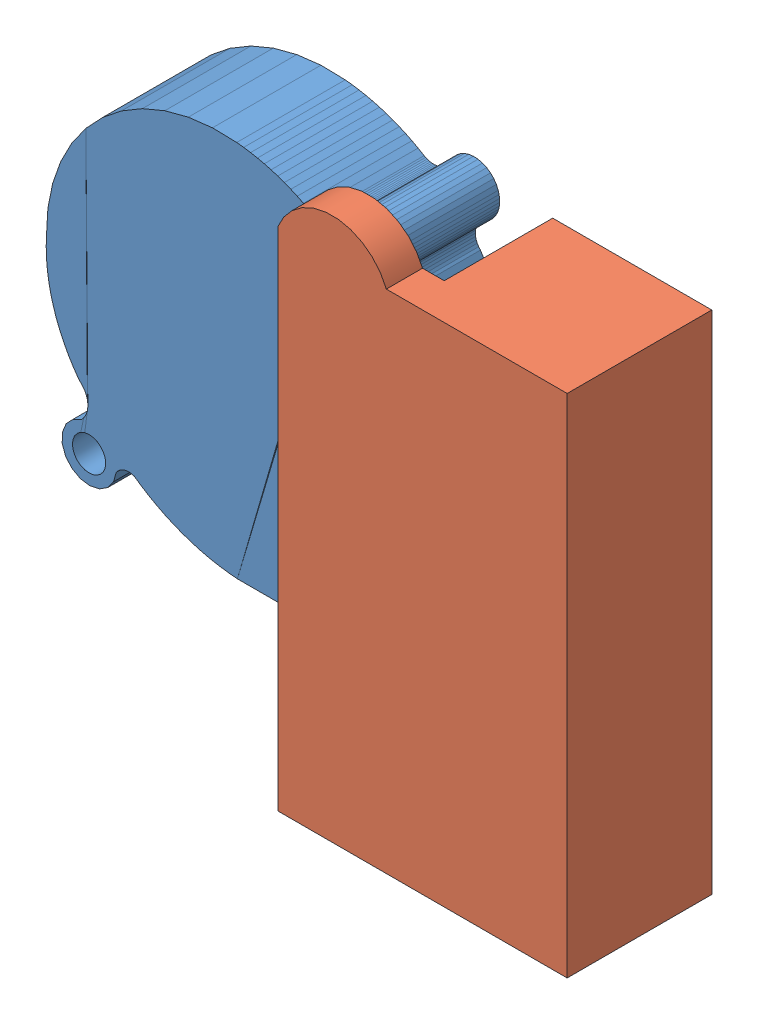
SolidWorks assembly Fan with holder, configuration Default. Lengths in mm.
Overall size (77.32 75.08 20).
3 component instances, 2 part files, 4 mates.
Components (placement in the parent):
- fan-1: fan [Default] at (-101.1742 42.521 95.7483) size (52.32 54.01 15)
  - Component_3-1: Component_3 [Default] at (137.5608 37.6442 10.5) x (-1 0 0) z (0 0 1) size (52.32 54.01 15)
- fan holder-1: fan holder [Default] at (47.4054 34.0076 118.7483) x (0 1 0) z (-1 0 0) size (75.08 20 40)
Mates (geometry in assembly coordinates):
- Coincident2: coincident anti-aligned: plane of fan-1/Component_3-1 through (36.3867 80.1652 98.7483) normal (0 0 1); plane of fan holder-1 through (47.4054 34.0076 98.7483) normal (0 0 -1)
- Distance1: distance = 22.5 mm: line of fan-1/Component_3-1 through (62.4054 54.0076 98.7483) axis (0 1 0); line of fan holder-1 through (84.9054 84.0076 98.7483) axis (0 -1 0)
- Perpendicular1: perpendicular: plane of fan-1/Component_3-1 through (62.4054 80.1652 106.2483) normal (1 0 0); plane of fan holder-1 through (62.4054 54.0076 113.7483) normal (0 1 0)
- Coincident6: coincident anti-aligned: plane of fan-1/Component_3-1 through (62.4054 54.0076 113.7483) normal (0 -1 0); plane of fan holder-1 through (62.4054 54.0076 113.7483) normal (0 1 0)
